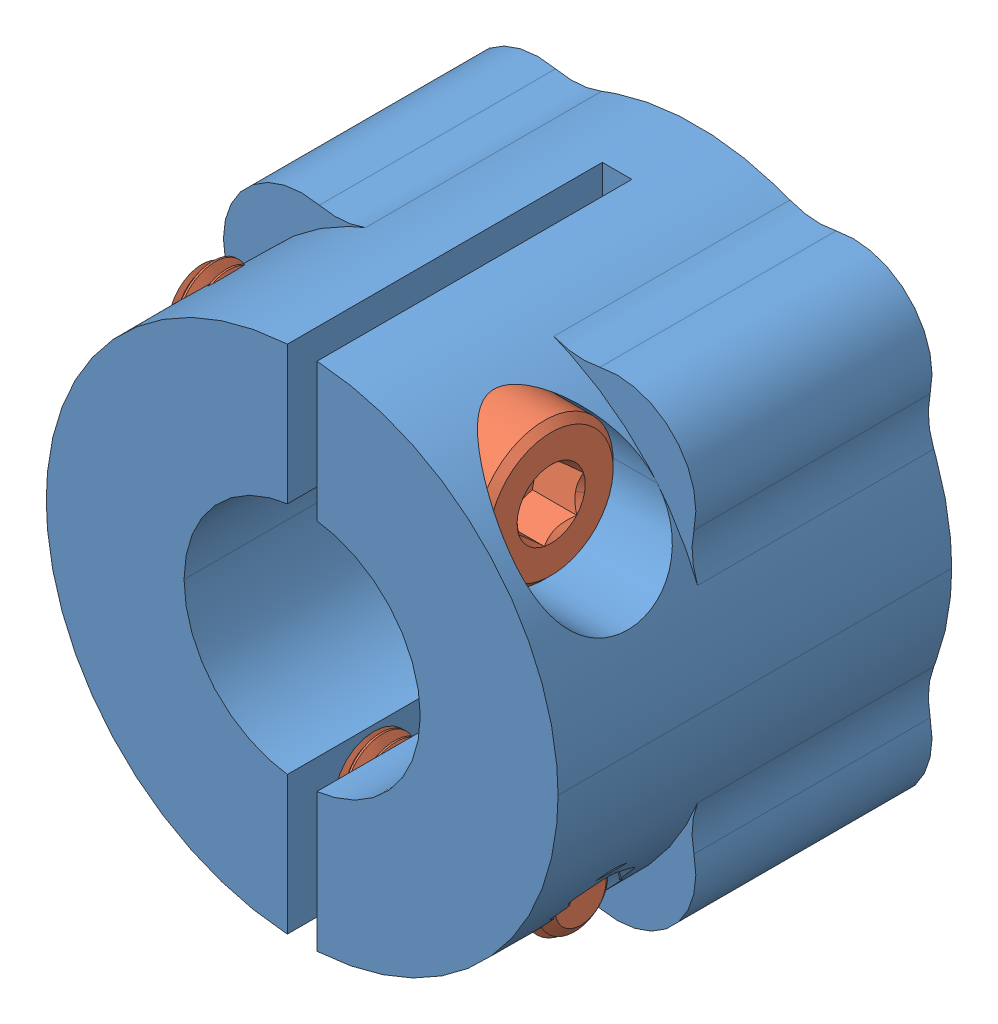
SolidWorks assembly 12mm Hyper Hub 1310-0016-0012, configuration Default. Lengths in mm.
Overall size (26 26 22).
3 component instances, 2 part files, 0 mates.
Components (placement in the parent):
- 1310-0016-0012.STEP-1: 1310-0016-0012.STEP [Default] at (-46.7501 4.892 12.3459) size (26 26 22)
- 2800-0004-0014_90128A207.STEP-1: 2800-0004-0014_90128A207.STEP [Default] at (-56.5001 13.142 27.9459) x (0 0.199975 0.979801) z (-1 0 0) size (7 7 18.01)
- 2800-0004-0014_90128A207.STEP-2: 2800-0004-0014_90128A207.STEP [Default] at (-37.0001 -3.358 27.9459) x (0 -0.199975 0.979801) z (1 0 0) size (7 7 18.01)
